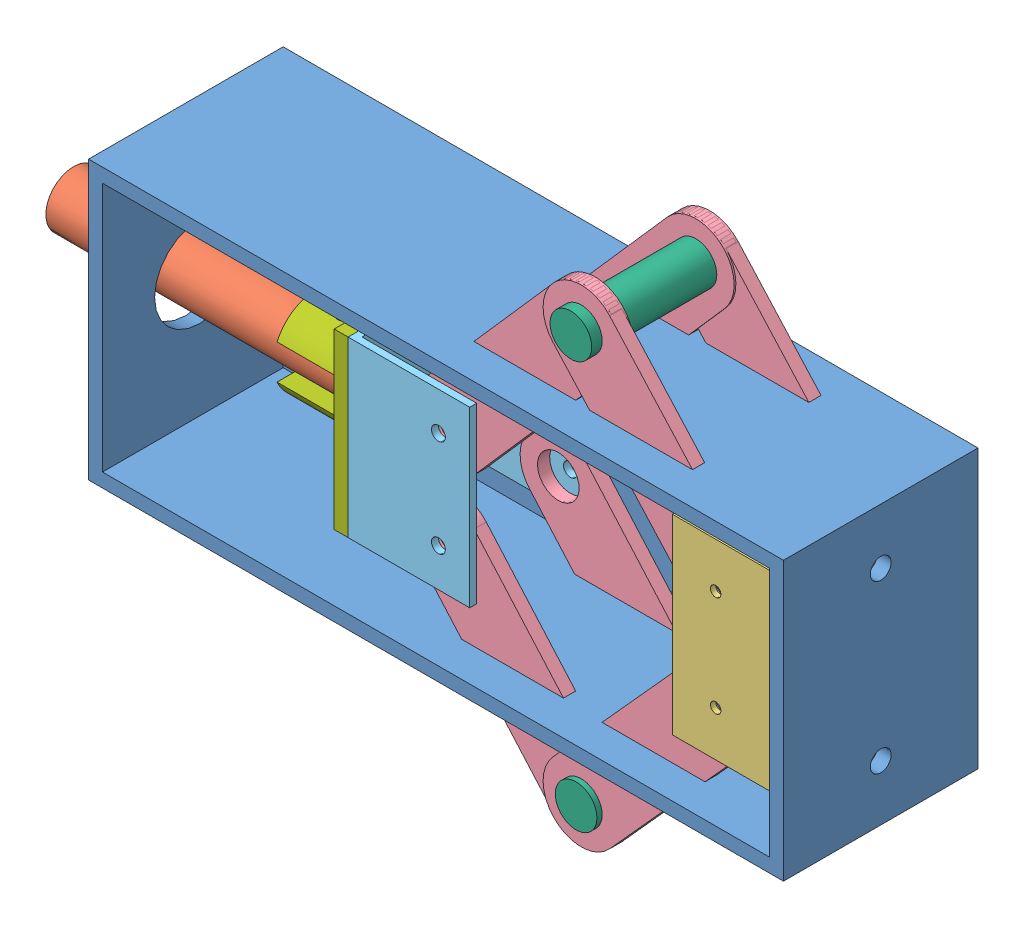
SolidWorks assembly 测绘装配, configuration 默认. Lengths in mm.
Overall size (232.3 149.19 56).
15 component instances, 7 part files, 38 mates.
Components (placement in the parent):
- 箱体-1: 箱体 [默认] at origin size (200 80 56)
- 伸出最长的长度-1: 伸出最长的长度 [默认] at (-42.3045 0 28) x (-1 0 0) z (0 -1 0) size (90 16 16)
- 实际底-2: 实际底 [默认] at (95 0 28) x (0 1 0) z (1 0 0) size (70 40 36)
- 杆-1: 杆 [默认] at (52.4085 36.7785 43) x (0.669717 -0.742617 0) z (0 0 1) size (82 22 3.5)
- 杆-2: 杆 [默认] at (52.4085 -36.7785 43) x (0.669717 0.742617 0) z (0 0 1) size (82 22 3.5)
- 杆-3: 杆 [默认] at (52.4085 -36.7785 9.5) x (0.669717 0.742617 0) z (0 0 1) size (82 22 3.5)
- 杆-4: 杆 [默认] at (52.4085 36.7785 9.5) x (0.669717 -0.742617 0) z (0 0 1) size (82 22 3.5)
- 实际顶-1: 实际顶 [默认] at (1.6955 0 28) x (0 1 0) z (0 0 1) size (50 35 40)
- 杆-5: 杆 [默认] at (12.5062 -36.5285 10) x (0.660359 -0.75095 0) z (0 0 1) size (82 22 3.5)
- 杆-6: 杆 [默认] at (12.5062 36.5285 42.5) x (-0.660359 -0.75095 0) z (0 0 1) size (82 22 3.5)
- 杆-7: 杆 [默认] at (12.5062 36.5285 10) x (0.660359 0.75095 0) z (0 0 1) size (82 22 3.5)
- 杆-8: 杆 [默认] at (12.5062 -36.5285 42.5) x (0.660359 -0.75095 0) z (0 0 1) size (82 22 3.5)
- 中间连接-1: 中间连接 [默认] at (32.317 -59.057 28) size (12 12 40)
- 中间连接-2: 中间连接 [默认] at (32.317 59.057 29.5) size (12 12 40)
- 连接结构2-1: 连接结构2 [默认] at (-33.3045 0 28) x (0 1 0) z (0 0 1) size (50 29 40)
Mates (geometry in assembly coordinates):
- 同心1: concentric anti-aligned: circle of 箱体-1; circle of 伸出最长的长度-1
- 平行1: parallel anti-aligned: plane of 箱体-1 through (-96 36 4) normal (0 -1 0); plane of 伸出最长的长度-1 through (-62.3045 5 18) normal (0 1 0)
- 同心4: concentric aligned: circle of 箱体-1; circle of 实际底-2
- 同心5: concentric aligned: circle of 箱体-1; circle of 实际底-2
- 重合3: coincident anti-aligned: plane of 箱体-1 through (96 36 4) normal (-1 0 0); plane of 实际底-2 through (96 0 28) normal (1 0 0)
- 同心6: concentric aligned: circle of 实际底-2; circle of 杆-3
- 重合4: coincident anti-aligned: plane of 实际底-2 through (95 0 9.5) normal (0 0 1); plane of 杆-3 through (72.5 -14.5 9.5) normal (0 0 -1)
- 同心7: concentric aligned: circle of 实际底-2; circle of 杆-2
- 重合5: coincident anti-aligned: plane of 实际底-2 through (95 0 46.5) normal (0 0 -1); plane of 杆-2 through (72.5 -14.5 46.5) normal (0 0 1)
- 同心8: concentric aligned: circle of 实际底-2; circle of 杆-4
- 重合6: coincident anti-aligned: plane of 实际底-2 through (95 0 9.5) normal (0 0 1); plane of 杆-4 through (72.5 14.5 9.5) normal (0 0 -1)
- 同心9: concentric aligned: circle of 实际底-2; circle of 杆-1
- 重合7: coincident anti-aligned: plane of 实际底-2 through (95 0 46.5) normal (0 0 -1); plane of 杆-1 through (72.5 14.5 46.5) normal (0 0 1)
- 平行2: parallel anti-aligned: plane of 实际底-2 through (60 -27.5 46.5) normal (-1 0 0); plane of 实际顶-1 through (1.6955 25 48) normal (1 0 0)
- 重合8: coincident anti-aligned: plane of 伸出最长的长度-1; plane of 实际顶-1 through (1.6955 0 28) normal (0 0 1)
- 重合9: coincident anti-aligned: plane of 伸出最长的长度-1 through (-42.3045 0 28) normal (0 -1 0); plane of 实际顶-1
- 同心10: concentric anti-aligned: circle of 实际顶-1; circle of 杆-5
- 重合10: coincident anti-aligned: plane of 实际顶-1 through (-31.3045 25 10) normal (0 0 1); plane of 杆-5 through (32.317 -59.057 10) normal (0 0 -1)
- 同心11: concentric aligned: circle of 实际顶-1; circle of 杆-8
- 重合11: coincident anti-aligned: plane of 实际顶-1 through (-31.3045 25 46) normal (0 0 -1); plane of 杆-8 through (32.317 -59.057 46) normal (0 0 1)
- 同心12: concentric anti-aligned: circle of 实际顶-1; circle of 杆-7
- 重合12: coincident anti-aligned: plane of 实际顶-1 through (-31.3045 25 10) normal (0 0 1); plane of 杆-7 through (32.317 59.057 10) normal (0 0 -1)
- 同心13: concentric aligned: circle of 实际顶-1; circle of 杆-6
- 重合13: coincident anti-aligned: plane of 实际顶-1 through (-31.3045 25 46) normal (0 0 -1); plane of 杆-6 through (-7.3045 14 46) normal (0 0 1)
- 同心14: concentric aligned: circle of 杆-3; circle of 中间连接-1
- 重合14: coincident aligned: plane of 实际顶-1 through (-33.3045 25 8) normal (0 0 -1); plane of 中间连接-1 through (32.317 -59.057 8) normal (0 0 -1)
- 同心15: concentric aligned: circle of 杆-2; circle of 中间连接-1
- 同心16: concentric aligned: circle of 杆-8; circle of 中间连接-1
- 同心17: concentric anti-aligned: circle of 杆-5; cylinder of 中间连接-1 through (32.317 -59.057 48) axis (0 0 -1) radius 6
- 同心18: concentric aligned: circle of 杆-4; circle of 中间连接-2
- 重合15: coincident anti-aligned: plane of 杆-4 through (72.5 14.5 9.5) normal (0 0 -1); circle of 中间连接-2
- 同心19: concentric aligned: circle of 杆-1; circle of 中间连接-2
- 同心20: concentric aligned: circle of 杆-7; circle of 中间连接-2
- 同心21: concentric aligned: circle of 杆-6; circle of 中间连接-2
- 重合16: coincident anti-aligned: plane of 实际顶-1 through (-33.3045 25 48) normal (-1 0 0); plane of 连接结构2-1 through (-33.3045 0 28) normal (1 0 0)
- 重合17: coincident aligned: plane of 实际顶-1 through (-33.3045 25 48) normal (0 0 1); plane of 连接结构2-1 through (-37.3045 -25 48) normal (0 0 1)
- 重合18: coincident aligned: plane of 实际顶-1 through (1.6955 25 28) normal (0 1 0); plane of 连接结构2-1 through (-37.3045 25 8) normal (0 1 0)
- 重合19: coincident anti-aligned: plane of 伸出最长的长度-1 through (-42.3045 0 28) normal (1 0 0); plane of 连接结构2-1 through (-42.3045 -5 8) normal (-1 0 0)
